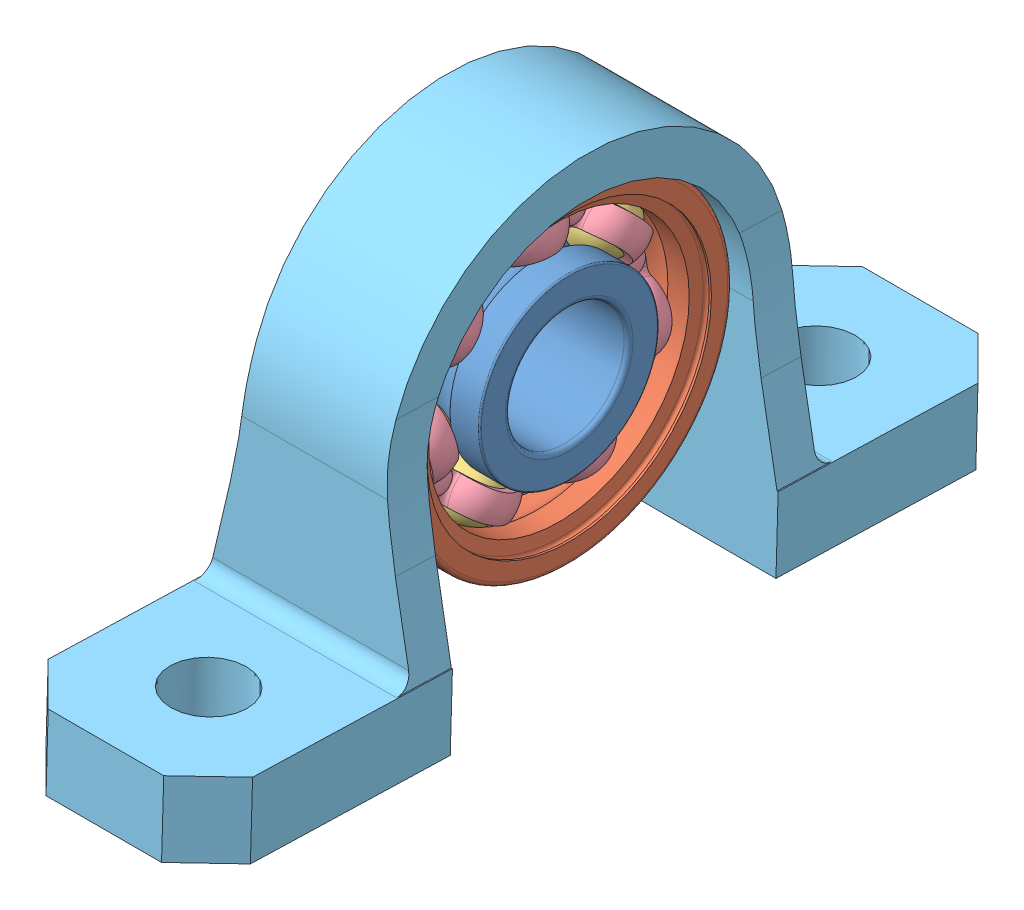
SolidWorks assembly K08, configuration Default. Lengths in mm.
Overall size (13.8 30.31 55.82).
12 component instances, 5 part files, 2 mates.
Components (placement in the parent):
- 608-1: 608 [SKF 608] at (4.194 28.9751 30.2057) size (7 22 22)
  - 608 Inner Race^608-1: 608 Inner Race^608 [Default] at origin size (7 12.1 12.1) (virtual)
  - 608 Outer Race^608-1: 608 Outer Race^608 [Default] at origin size (7 22 22) (virtual)
  - 608 Ball^608-1: 608 Ball^608 [Default] at origin size (3.97 3.97 3.97) (virtual)
  - 608 Ball^608-2: 608 Ball^608 [Default] x (1 0 0) z (0 -0.781831 0.62349) size (3.97 3.97 3.97) (virtual)
  - 608 Ball^608-3: 608 Ball^608 [Default] x (1 0 0) z (0 -0.974928 -0.222521) size (3.97 3.97 3.97) (virtual)
  - 608 Ball^608-4: 608 Ball^608 [Default] x (1 0 0) z (0 -0.433884 -0.900969) size (3.97 3.97 3.97) (virtual)
  - 608 Ball^608-5: 608 Ball^608 [Default] x (1 0 0) z (0 0.433884 -0.900969) size (3.97 3.97 3.97) (virtual)
  - 608 Ball^608-6: 608 Ball^608 [Default] x (1 0 0) z (0 0.974928 -0.222521) size (3.97 3.97 3.97) (virtual)
  - 608 Ball^608-7: 608 Ball^608 [Default] x (1 0 0) z (0 0.781831 0.62349) size (3.97 3.97 3.97) (virtual)
  - Ball retainer rings^608-1: Ball retainer rings^608 [Default] at (3.5 0 0) x (0 0 -1) z (1 0 0) size (16.6 16.6 4.97) (virtual)
- K08-1: K08 [Default] at (2.994 28.9751 30.2057) x (0 -0.029524 -0.999564) z (1 0 0) size (55 28.7 13.8)
Mates (geometry in assembly coordinates):
- Concentric1: concentric anti-aligned: cylinder of 608-1/608 Outer Race^608-1 through (10.894 28.9751 30.2057) axis (1 0 0) radius 11; cylinder of K08-1 through (12.394 28.9751 30.2057) axis (-1 0 0) radius 11
- Distance1: distance = 1.2 mm aligned: plane of 608-1/608 Outer Race^608-1 through (11.194 38.5751 30.2057) normal (1 0 0); plane of K08-1 through (12.394 28.9751 30.2057) normal (1 0 0)
